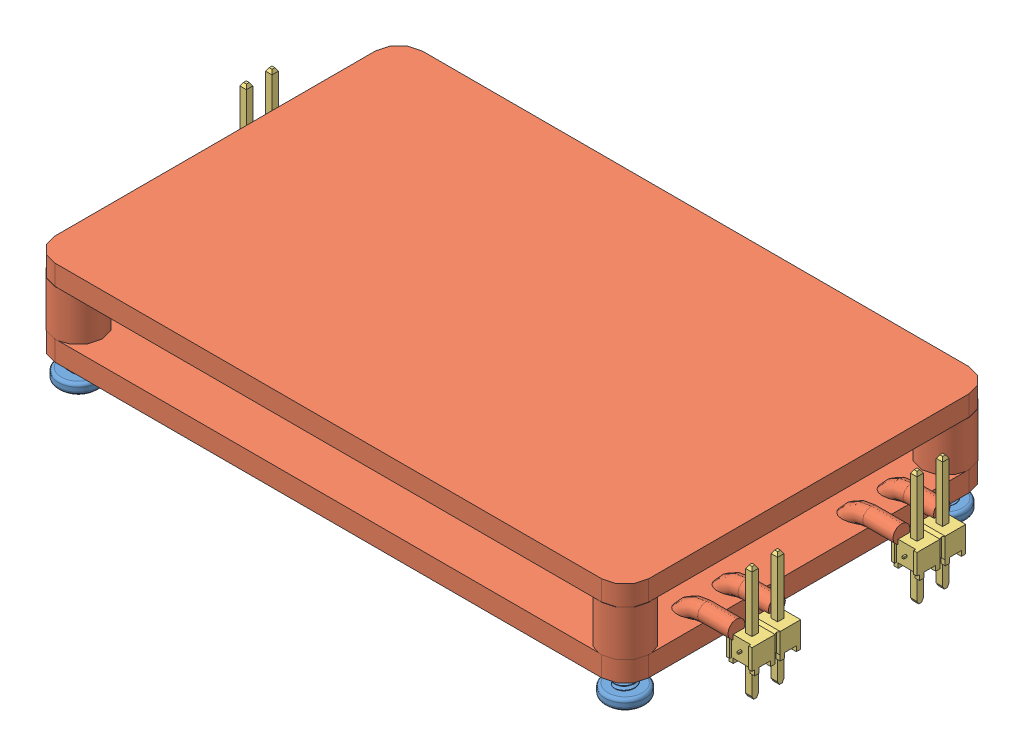
SolidWorks assembly BatteryMonitorAssembly, configuration Default. Lengths in mm.
Overall size (68.99 11.71 36.95).
8 component instances, 3 part files, 15 mates.
Components (placement in the parent):
- 92000A012_Passivated 18-8 Stainless Steel Pan Head Phillips Screws-1: 92000A012_Passivated 18-8 Stainless Steel Pan Head Phillips Screws [92000A012] at (-27.09 3.4 15.875) x (0.702544 0 0.711641) z (0 -1 0) size (4 4 6.68)
- BatteryMonitor-1: BatteryMonitor [Default] at origin size (64.83 8.5 36.45)
- 92000A012_Passivated 18-8 Stainless Steel Pan Head Phillips Screws-2: 92000A012_Passivated 18-8 Stainless Steel Pan Head Phillips Screws [92000A012] at (27.09 3.4 15.875) x (-0.99989 0 -0.014831) z (0 -1 0) size (4 4 6.68)
- 92000A012_Passivated 18-8 Stainless Steel Pan Head Phillips Screws-3: 92000A012_Passivated 18-8 Stainless Steel Pan Head Phillips Screws [92000A012] at (27.09 3.4 -15.875) x (-0.209713 0 0.977763) z (0 -1 0) size (4 4 6.68)
- 92000A012_Passivated 18-8 Stainless Steel Pan Head Phillips Screws-4: 92000A012_Passivated 18-8 Stainless Steel Pan Head Phillips Screws [92000A012] at (-27.09 3.4 -15.875) x (0.991519 0 -0.12996) z (0 -1 0) size (4 4 6.68)
- TSW-150-23-T-S_2-1: TSW-150-23-T-S_2 [Default] at (-33.225 0 -69.135) x (0 0 -1) z (1 0 0) size (5.21 11.3 2.54)
- TSW-150-23-T-S_2-3: TSW-150-23-T-S_2 [Default] at (33.225 0 -52.785) x (0 0 -1) z (1 0 0) size (5.21 11.3 2.54)
- TSW-150-23-T-S_2-4: TSW-150-23-T-S_2 [Default] at (33.225 0 -69.135) x (0 0 -1) z (1 0 0) size (5.21 11.3 2.54)
Mates (geometry in assembly coordinates):
- Coincident1: coordinate: unknown of BatteryMonitor-1
- Concentric1: concentric aligned: circle of BatteryMonitor-1; cylinder of 92000A012_Passivated 18-8 Stainless Steel Pan Head Phillips Screws-4 through (-27.09 3.4 -15.875) axis (0 1 0) radius 2
- Concentric2: concentric anti-aligned: cylinder of 92000A012_Passivated 18-8 Stainless Steel Pan Head Phillips Screws-1 through (-27.09 3.4 15.875) axis (0 1 0) radius 2; cylinder of BatteryMonitor-1 through (-27.09 2 15.875) axis (0 -1 0) radius 2.325
- Concentric3: concentric aligned: circle of BatteryMonitor-1; circle of 92000A012_Passivated 18-8 Stainless Steel Pan Head Phillips Screws-3
- Concentric4: concentric anti-aligned: cylinder of BatteryMonitor-1 through (27.09 2 15.875) axis (0 -1 0) radius 2.325; circle of 92000A012_Passivated 18-8 Stainless Steel Pan Head Phillips Screws-2
- Coincident2: coincident aligned: plane of 92000A012_Passivated 18-8 Stainless Steel Pan Head Phillips Screws-2 through (27.09 -1.6 15.875) normal (0 1 0); plane of 92000A012_Passivated 18-8 Stainless Steel Pan Head Phillips Screws-3 through (27.09 -1.6 -15.875) normal (0 1 0)
- Coincident3: coincident aligned: plane of 92000A012_Passivated 18-8 Stainless Steel Pan Head Phillips Screws-1 through (-27.09 -1.6 15.875) normal (0 1 0); plane of 92000A012_Passivated 18-8 Stainless Steel Pan Head Phillips Screws-2 through (27.09 -1.6 15.875) normal (0 1 0)
- Coincident4: coincident aligned: plane of 92000A012_Passivated 18-8 Stainless Steel Pan Head Phillips Screws-1 through (-27.09 -1.6 15.875) normal (0 1 0); plane of 92000A012_Passivated 18-8 Stainless Steel Pan Head Phillips Screws-4 through (-27.09 -1.6 -15.875) normal (0 1 0)
- Distance1: distance = 1.6 mm anti-aligned: plane of 92000A012_Passivated 18-8 Stainless Steel Pan Head Phillips Screws-1 through (-27.09 -1.6 15.875) normal (0 1 0); plane of BatteryMonitor-1 through (26.565 0 10.175) normal (0 -1 0)
- Coincident5: coincident aligned: plane of BatteryMonitor-1 through (26.565 0 10.175) normal (0 -1 0); plane of TSW-150-23-T-S_2-1 through (-33.225 0 -69.135) normal (0 -1 0)
- Coincident9: coincident aligned: plane of TSW-150-23-T-S_2-3 through (35.765 0.508 10.4641) normal (0 -1 0); plane of TSW-150-23-T-S_2-4 through (35.765 0.508 -10.0323) normal (0 -1 0)
- Coincident10: coincident aligned: plane of TSW-150-23-T-S_2-3 through (31.955 2.54 -116.285) normal (-1 0 0); plane of TSW-150-23-T-S_2-4 through (31.955 2.54 -132.635) normal (-1 0 0)
- Distance2: distance = 2.54 mm anti-aligned: plane of BatteryMonitor-1 through (29.415 2 0) normal (1 0 0); plane of TSW-150-23-T-S_2-3 through (31.955 2.54 -116.285) normal (-1 0 0)
- Coincident16: coincident: line of TSW-150-23-T-S_2-4 through (34.241 2.286 -8.175) axis (-1 0 0)
- Width4: width aligned: plane of BatteryMonitor-1 through (-27.09 8.5 -18.2) normal (0 0 -1); plane of TSW-150-23-T-S_2-4 through (-27.09 8.5 18.2) normal (0 0 1); plane of BatteryMonitor-1 through (35.765 8.382 -9.7625) normal (0 0 -1); plane of TSW-150-23-T-S_2-3 through (33.5425 8.382 9.7625) normal (0 0 1)
